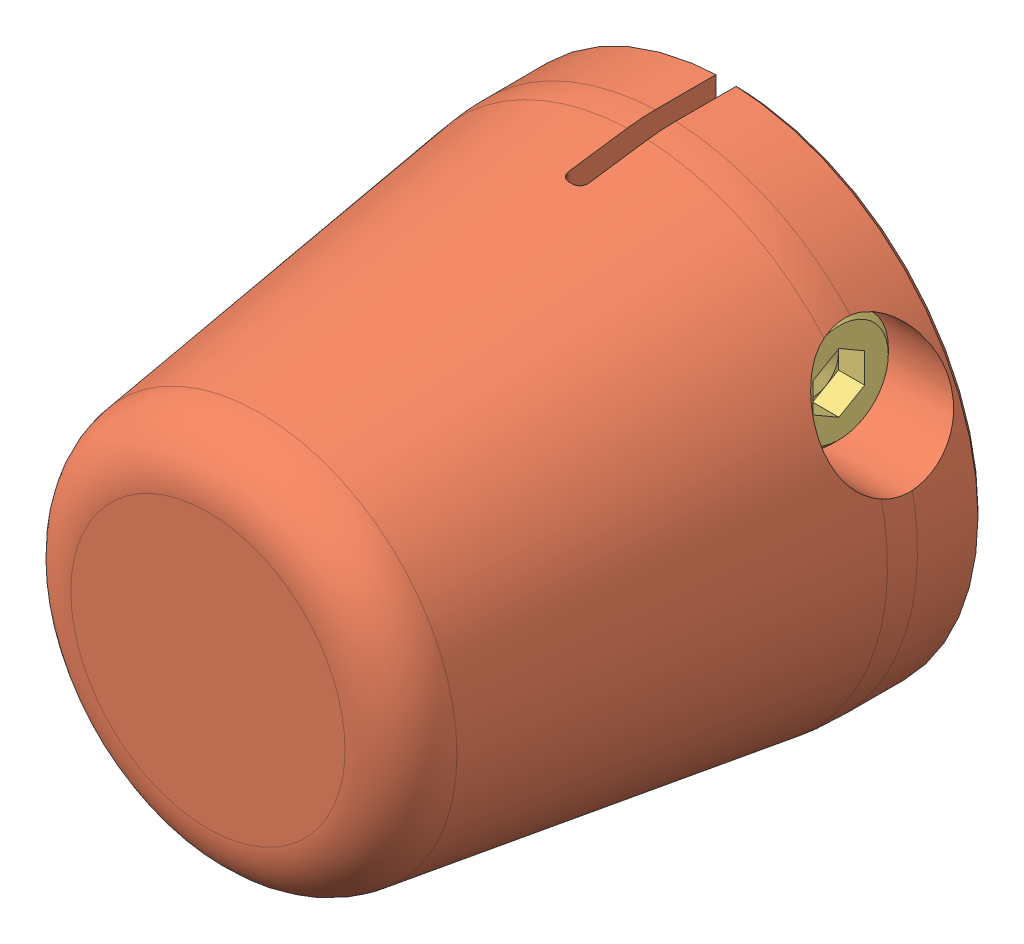
SolidWorks assembly Knob-1, configuration Default. Lengths in mm.
Overall size (25 25.09 26).
3 component instances, 3 part files, 0 mates.
Components (placement in the parent):
- square nut thin grade b_din(Square nut DIN 562 M3 -N)-1: square nut thin grade b_din(Square nut DIN 562 M3 -N) [Default] at (-4.7 5.5 3.5) x (0 0 1) z (-1 0 0) size (5.5 5.5 1.8)
- Knob-1: Knob [Default] at origin size (25 25.09 26)
- socket head cap screw_am(B18.3.1M - 3 x 0.5 x 12 Hex SHCS -- 12NHX)-1: socket head cap screw_am(B18.3.1M - 3 x 0.5 x 12 Hex SHCS -- 12NHX) [Default] at (8.8 5.5 3.5) x (-1 0 0) z (0 0 1) size (15 5.5 5.5)
